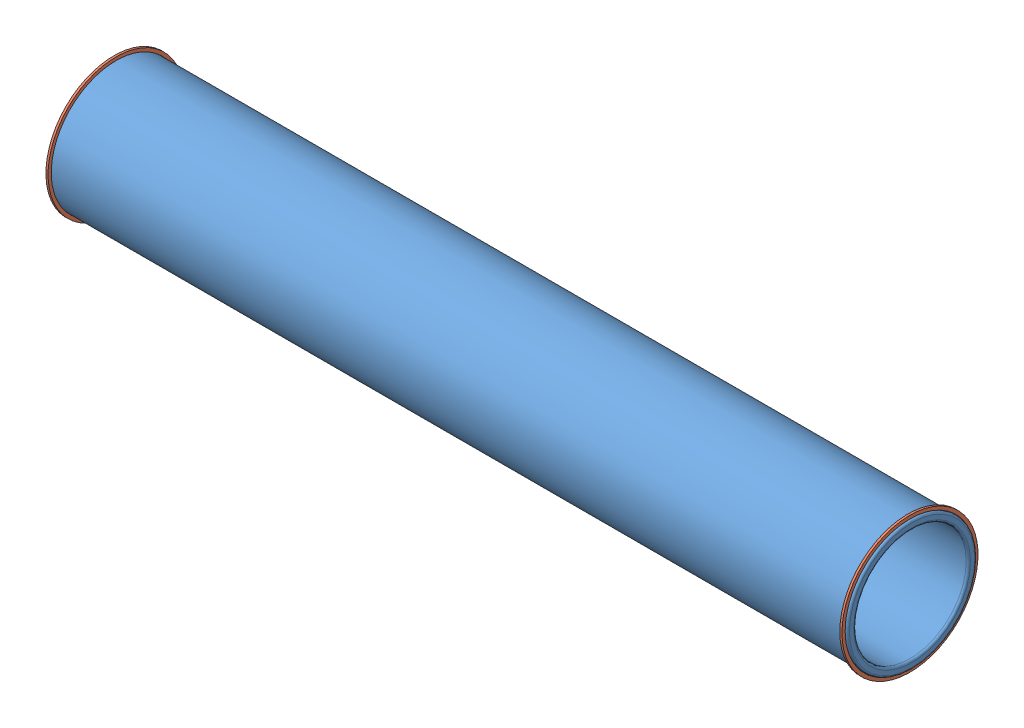
SolidWorks assembly Taker in assembly, configuration Default. Lengths in mm.
Overall size (750 132.97 132.97).
3 component instances, 2 part files, 4 mates.
Components (placement in the parent):
- Taker in-1: Taker in [Default] at (-443.8271 21.8601 21.4677) size (750 121.5 121.5)
- Taker in ring-1: Taker in ring [Default] at (-441.8271 21.8601 21.4677) x (1 0 0) z (0 0.999038 -0.043846) size (2 127.5 127.5)
- Taker in ring-3: Taker in ring [Default] at (302.1729 21.8601 21.4677) size (2 127.5 127.5)
Mates (geometry in assembly coordinates):
- Concentric5: concentric: circle of Taker in-1; cylinder of Taker in ring-1 through (-502.4708 21.8601 21.4677) axis (-1 0 0) radius 60.75
- Concentric6: concentric: circle of Taker in-1; circle of Taker in ring-1
- Coincident1: coincident: circle of Taker in-1; circle of Taker in ring-1
- Coincident2: coincident: circle of Taker in-1; circle of Taker in ring-3
